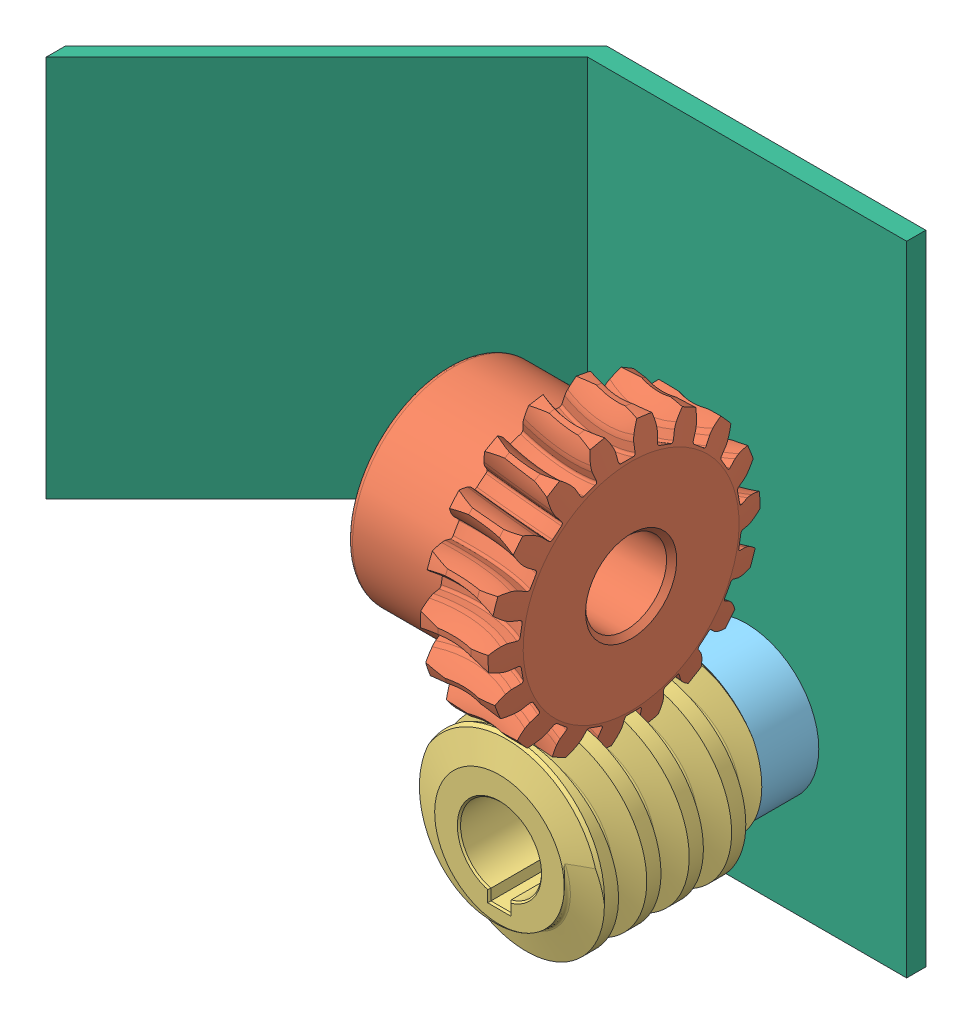
SolidWorks assembly CorrectPositionWrongScale, configuration Default. Lengths in mm.
Overall size (92.43 100 55.3).
8 component instances, 6 part files, 12 mates.
Components (placement in the parent):
- Base-1: Base [Default] at (2.2614 9.8598 -10.871) size (15 25 25)
- 57545K511_SPEED-REDUCING WORM GEAR FOR 90 DEG TRANSFER-1: 57545K511_SPEED-REDUCING WORM GEAR FOR 90 DEG TRANSFER [57545K511] at (20.3833 60.0141 14.0397) x (0 0 -1) z (0 1 0) size (44.78 28.61 44.18)
- 57545K527_SPEED-REDUCING WORM GEAR FOR 90 DEG TRANSFER-1: 57545K527_SPEED-REDUCING WORM GEAR FOR 90 DEG TRANSFER [57545K527] at (20.3833 28.2217 14.0397) x (-1 0 0) z (0 0 1) size (31.13 29.72 30.93)
- Shaft-1: Shaft [Default] at (2.2614 60.0141 14.0397) x (0 1 0) z (1 0 0) size (12.2 12.2 10)
- Shaft-2: Shaft [Default] at (20.3833 28.2217 -10.871) x (0.999869 0.016187 0) z (0 0 1) size (12.2 12.2 10)
- Spacer-1: Spacer [Default] at (20.3833 28.2217 -0.371) x (1 0 0) z (0 1 0) size (22.7 10 22.7)
- Spacer-2: Spacer [Default] at (2.7614 60.0141 14.0397) x (0 -1 0) z (0 0 1) size (22.7 10 22.7)
- AssemblyBase-1: AssemblyBase [Default] at (15.0036 48.5149 -15.871) x (0 1 0) z (1 0 0) size (100 45.43 92.43)
Mates (geometry in assembly coordinates):
- Coincident2: coincident: plane of Base-1 through (12.2614 9.8598 -10.871) normal (0 0 1); plane of Shaft-2 through (20.3833 28.2217 -10.871) normal (0 0 -1)
- Concentric1: concentric: cylinder of 57545K527_SPEED-REDUCING WORM GEAR FOR 90 DEG TRANSFER-1 through (20.3833 28.2217 14.0397) axis (0 0 1) radius 6.35; cylinder of Shaft-2 through (20.3833 28.2217 -0.871) axis (0 0 -1) radius 6.1
- Coincident4: coincident: plane of Base-1 through (2.2614 9.8598 -10.871) normal (1 0 0); plane of Shaft-1 through (2.2614 60.0141 14.0397) normal (-1 0 0)
- Concentric3: concentric: cylinder of 57545K511_SPEED-REDUCING WORM GEAR FOR 90 DEG TRANSFER-1 through (87.8119 60.0141 14.0397) axis (1 0 0) radius 6.35; cylinder of Shaft-1 through (12.2614 60.0141 14.0397) axis (-1 0 0) radius 6.1
- Coincident5: coincident: point of 57545K511_SPEED-REDUCING WORM GEAR FOR 90 DEG TRANSFER-1; circle of 57545K527_SPEED-REDUCING WORM GEAR FOR 90 DEG TRANSFER-1
- Coincident9: coincident: line of 57545K511_SPEED-REDUCING WORM GEAR FOR 90 DEG TRANSFER-1 through (20.3833 40.9641 14.0397) axis (0 1 0); line of 57545K527_SPEED-REDUCING WORM GEAR FOR 90 DEG TRANSFER-1 through (20.3833 28.2217 14.0397) axis (0 -1 0)
- Concentric6: concentric: cylinder of Shaft-2 through (20.3833 28.2217 -0.871) axis (0 0 -1) radius 6.1; cylinder of Spacer-1 through (20.3833 28.2217 -10.371) axis (0 0 1) radius 6.35
- Concentric7: concentric: cylinder of 57545K511_SPEED-REDUCING WORM GEAR FOR 90 DEG TRANSFER-1 through (87.8119 60.0141 14.0397) axis (1 0 0) radius 6.35; cylinder of Spacer-2 through (12.7614 60.0141 14.0397) axis (-1 0 0) radius 6.35
- Distance1: distance = 0.5 mm: plane of Shaft-1 through (2.2614 60.0141 14.0397) normal (-1 0 0); plane of Spacer-2 through (2.7614 60.0141 14.0397) normal (-1 0 0)
- Distance2: distance = 0.5 mm: plane of Spacer-1 through (20.3833 28.2217 -10.371) normal (0 0 -1); plane of Shaft-2 through (20.3833 28.2217 -10.871) normal (0 0 -1)
- Coincident12: coincident: plane of Base-1 through (12.2614 29.8598 -15.871) normal (0 0 -1); plane of AssemblyBase-1 through (15.0036 48.5149 -15.871) normal (0 0 1)
- Parallel1: parallel: plane of Base-1 through (12.2614 9.8598 -10.871) normal (1 0 0); plane of AssemblyBase-1 through (40.0036 -1.4851 -18.871) normal (1 0 0)
